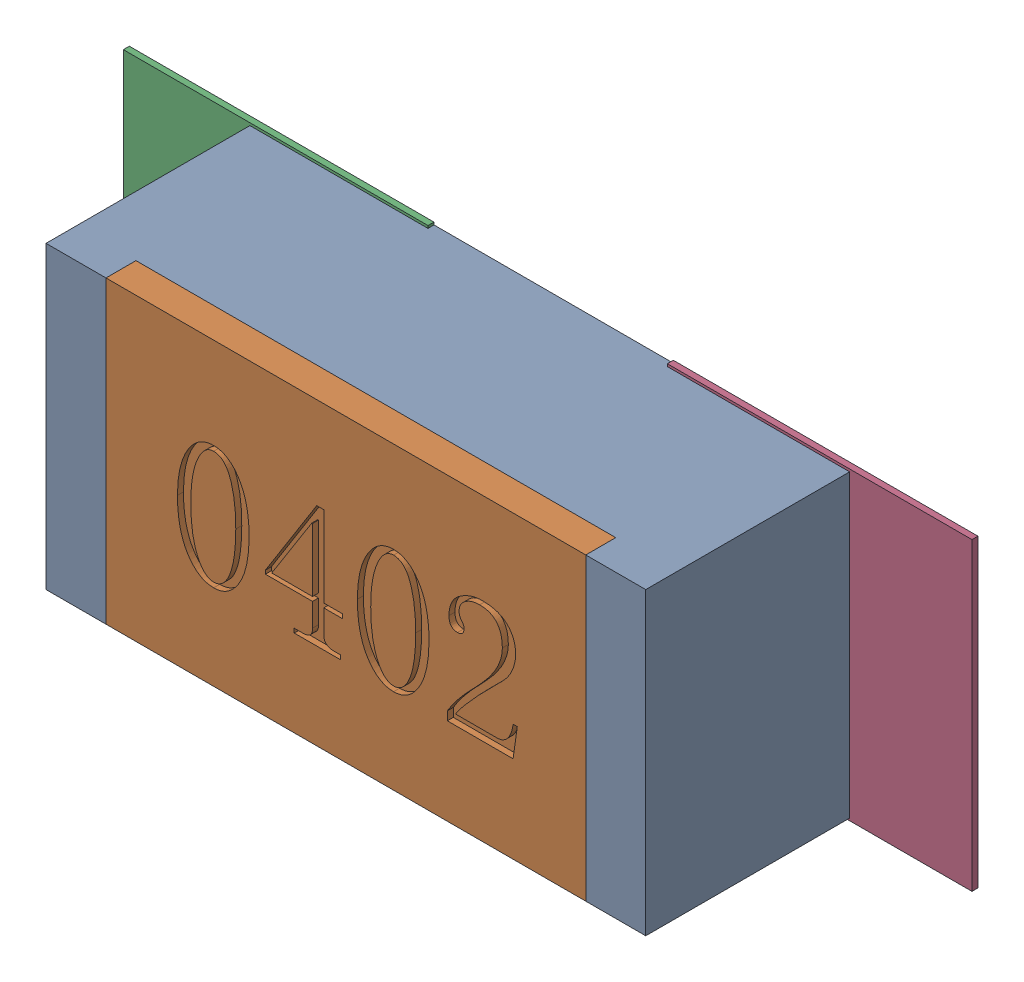
SolidWorks assembly R108, configuration Défaut. Lengths in mm.
Overall size (1.42 0.51 0.35).
5 component instances, 2 part files, 0 mates.
Components (placement in the parent):
- R0402-1: R0402 [Défaut] at (66.04 -14.4781 0) x (1 0 0) z (0 0 1) size (1 0.5 0.35)
- 6504207776-1: 6504207776 [Défaut] at (65.5829 -14.478 0) size (0.51 0.51 0.01)
  - Extruded-1: Extruded [Défaut] at origin size (0.51 0.51 0.01)
- 6504207776-2: 6504207776 [Défaut] at (66.49 -14.478 0) size (0.51 0.51 0.01)
  - Extruded-1: Extruded [Défaut] at origin size (0.51 0.51 0.01)
